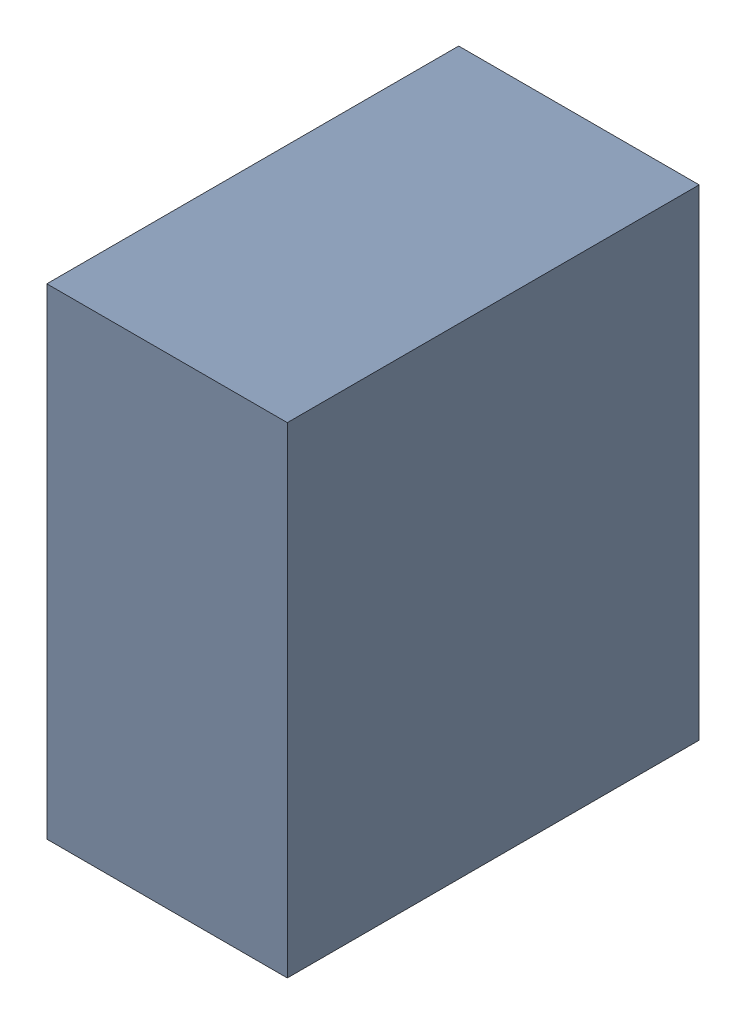
SolidWorks assembly U6Kanaloa_v2.0.0_Motor, configuration Default. Lengths in mm.
Overall size (0.51 1.02 0.87).
2 component instances, 1 part files, 0 mates.
Components (placement in the parent):
- 352878160-1: 352878160 [Default] at (66.04 110.3142 0.25) size (0.51 1.02 0.87)
  - Extruded_4-1: Extruded_4 [Default] at origin size (0.51 1.02 0.87)
